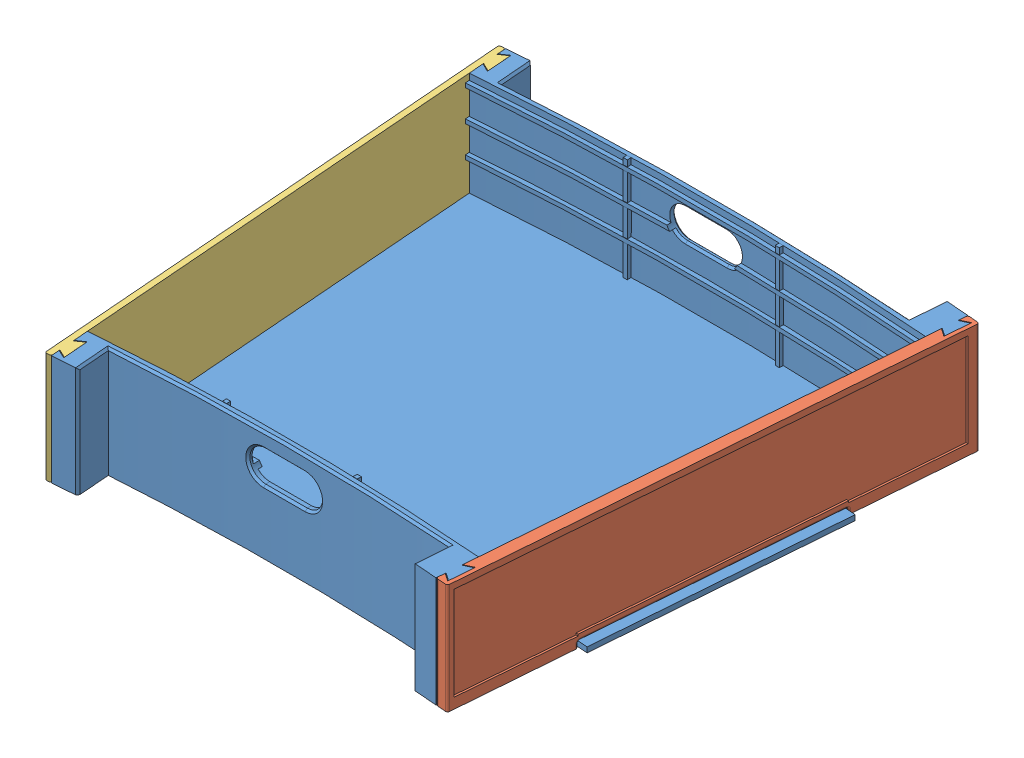
SolidWorks assembly side_parts_assemb, configuration Default. Lengths in mm.
Overall size (231.23 53 238.58).
3 component instances, 3 part files, 6 mates.
Components (placement in the parent):
- new_terrain_piece-1: new_terrain_piece [Default] at (-19.0871 -30.2929 1535.0918) size (227.81 53 238.12)
- side_part_female-1: side_part_female [Default] at (92.137 -30.2929 120.4575) x (0.996917 0 0.078459) z (0 1 0) size (5.9 238 53)
- side_part_male-1: side_part_male [Default] at (-111.6476 -30.2929 357.7246) x (-0.996917 0 0.078459) z (0 1 0) size (10.9 238 53)
Mates (geometry in assembly coordinates):
- Coincident1: coincident anti-aligned: plane of new_terrain_piece-1 through (-15.1991 46.6577 1535.3978) normal (0.996917 0 0.078459); plane of side_part-1 through (95.9911 22.7071 122.5915) normal (-0.996917 0 -0.078459)
- Coincident2: coincident aligned: plane of new_terrain_piece-1 through (-19.0871 22.7071 1535.0918) normal (0 1 0); plane of side_part-1 through (92.137 22.7071 120.4575) normal (0 1 0)
- Coincident3: coincident aligned: plane of new_terrain_piece-1 through (73.5731 46.6577 357.7325) normal (-0.078459 0 0.996917); plane of side_part-1 through (79.3455 22.7071 358.1868) normal (-0.078459 0 0.996917)
- Coincident6: coincident aligned: plane of new_terrain_piece-1 through (-111.7473 46.6577 357.7325) normal (0.078459 0 0.996917); plane of side_part_male-1 through (-114.5387 22.7071 357.9522) normal (0.078459 0 0.996917)
- Coincident8: coincident anti-aligned: plane of new_terrain_piece-1 through (-18.9874 46.6577 1535.084) normal (-0.996917 0 0.078459); plane of side_part_male-1 through (-111.6476 22.7071 357.7246) normal (0.996917 0 -0.078459)
- Coincident9: coincident aligned: plane of new_terrain_piece-1 through (-19.0871 22.7071 1535.0918) normal (0 1 0); plane of side_part_male-1 through (-111.6476 22.7071 357.7246) normal (0 1 0)
